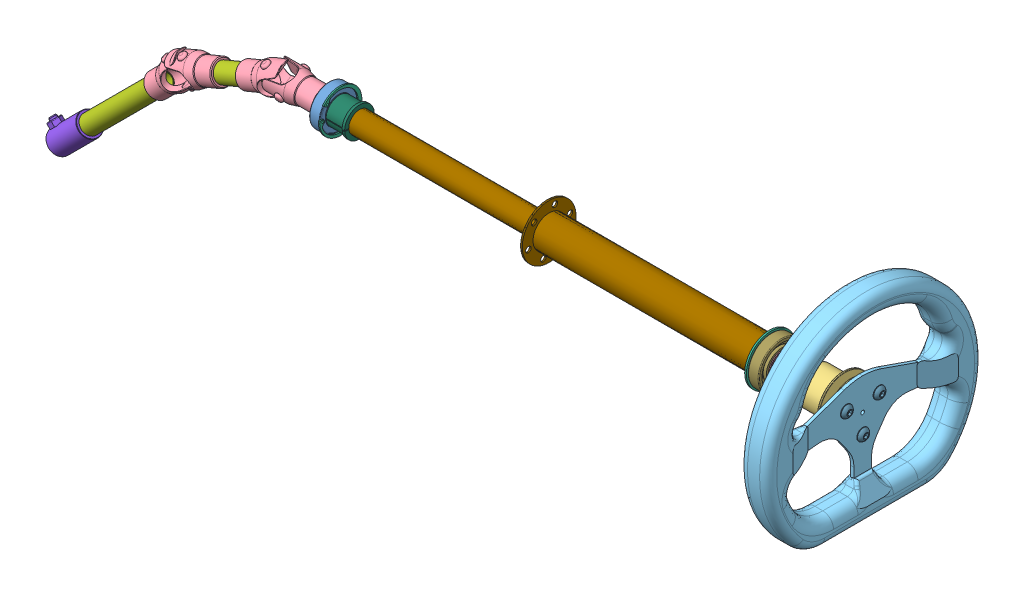
SolidWorks assembly SteeringColumn2SplineShaftFront, configuration Default. Lengths in mm.
Overall size (982.04 333.97 254.34).
24 component instances, 15 part files, 39 mates.
Components (placement in the parent):
- BearingBall6005-1: BearingBall6005 [Default] at (30.3546 0 0) x (0 1 0) z (0 0 1) size (47 12 47)
- WheelHubDisconnect-1: WheelHubDisconnect [Default] at (619.5484 0 0) x (1 0 0) z (0 -0.866763 0.498721) size (86.3 64.09 61.9)
  - SteeringWheelDisconnectSpline-1: SteeringWheelDisconnectSpline [Default] at origin size (55 25.4 25.4)
  - SteeringWheelDisconnect-1: SteeringWheelDisconnect [Default] at (31.3 0 0) x (0 0 -1) z (1 0 0) size (61.9 64.09 54.6)
- U-JointWoodward-1: U-JointWoodward [Default] at (-28.974 0 0) x (-1 0 0) z (0 -0.90881 -0.41721) size (73.55 38.86 33.16)
- SteeringWheel-1: SteeringWheel [Default] at (652.8042 0 0) x (0 -0.001477 0.999999) z (-1 0 0) size (254 227.58 56.05)
- Basic Internal Retaining Ring_am-1: Basic Internal Retaining Ring_am [B27.7M - 3BM1-47] at (36.3546 0 0) x (0 0.93649 -0.350695) z (-1 0 0) size (49.8 48.83 1.6)
- Basic Internal Retaining Ring_am-2: Basic Internal Retaining Ring_am [B27.7M - 3BM1-55] at (546.526 0 0) x (0 0.021414 -0.999771) z (1 0 0) size (58.4 57.21 2)
- U-JointDoubleMid-1: U-JointDoubleMid [Default] at (-87.086 -24.0708 0) x (-0.0561 0.135437 -0.989196) z (0.378549 -0.913898 -0.146596) size (42.36 158.5 46.32)
  - TubeSteering.75-1: TubeSteering.75 [DoubleUJoint] x (1 0 0) z (0 1 0) size (21.34 21.34 56.2)
  - U-JointWoodward-1: U-JointWoodward [Default] at (0 62.9 0) x (0 1 0) z (0.963512 0 -0.267666) size (73.55 38.86 33.16)
  - U-JointWoodward-2: U-JointWoodward [Default] at (0 -62.9 0) x (0 -1 0) z (0.963512 0 -0.267666) size (73.55 38.86 33.16)
- U-JointWoodward-2: U-JointWoodward [Default] at (-145.198 -48.1416 0) x (0.707107 0.707107 0) z (0.204327 -0.204327 0.95734) size (73.55 38.86 33.16)
- Coupler.75SmoothTo.625-36Spline-1: Coupler.75SmoothTo.625-36Spline [Default] at (-276.3664 -179.3099 0) x (0 0 -1) z (0.707107 0.707107 0) size (26.9 35.2 50.8)
- TubeSteering.75-1: TubeSteering.75 [RackToUJoint] at (-218.5957 -121.5393 0) x (-0.399395 0.399395 0.825208) z (0.707107 0.707107 0) size (21.34 21.34 138)
- SteeringColumn-1: SteeringColumn [Default] at (21.526 0 0) x (0 -0.699357 0.714773) z (-1 0 0) size (63.5 63.5 523.4)
- AdapterUJointToColumn-1: AdapterUJointToColumn [Default] at (18.526 0 0) x (0 0 1) z (-1 0 0) size (21.34 21.34 15)
- AdapterHubToColumn-1: AdapterHubToColumn [Default] at (553.026 0 0) x (0 -0.393267 0.919424) z (-1 0 0) size (41.1 41.1 29.62)
- Radial Ball Bearing_68_SKF-1: Radial Ball Bearing_68_SKF [SKF - 6006 - 14,SI,NC,14_68] at (553.026 0 0) x (-1 0 0) z (0 0.980666 0.195687) size (13 55 55)
- Basic External Retaining Ring_wti-1: Basic External Retaining Ring_wti [Truarc 5100-112 - S1.125] at (559.526 0 0) x (0 0 1) z (-1 0 0) size (31.9 34.77 1.27)
- Socket Button Head Cap Screw_AI-1: Socket Button Head Cap Screw_AI [SBHCSCREW 0.3125-18x0.5-HX-N] at (658.9764 11.0841 19.2638) x (-1 0 0) z (0 0.924225 0.381849) size (16.92 13.89 13.89)
- Socket Button Head Cap Screw_AI-2: Socket Button Head Cap Screw_AI [SBHCSCREW 0.3125-18x0.5-HX-N] at (658.9764 -22.225 -0.0328) x (-1 0 0) z (0 0.924225 0.381849) size (16.92 13.89 13.89)
- Socket Button Head Cap Screw_AI-3: Socket Button Head Cap Screw_AI [SBHCSCREW 0.3125-18x0.5-HX-N] at (658.9764 11.1409 -19.231) x (-1 0 0) z (0 0.924225 0.381849) size (16.92 13.89 13.89)
- SteeringColumnBush-1: SteeringColumnBush [Default] at (44.3672 0 0) x (0 0.051402 -0.998678) z (1 0 0) size (34.99 35 31.4)
Mates (geometry in assembly coordinates):
- Coincident7502: coincident: plane of assembly; plane of assembly; plane of WheelHubDisconnect-1/SteeringWheelDisconnect-1 through (650.8484 7.9047 13.7382) normal (1 0 0); plane of SteeringWheel-1 through (650.8484 0 0) normal (-1 0 0)
- Coincident75142: coincident: plane of BearingBall6005-1 through (30.3546 0 0) normal (0 1 0); plane of assembly through (0 0 0) normal (0 1 0)
- Concentric836224: concentric: cylinder of Basic Internal Retaining Ring_am-1 through (37.9546 0 0) axis (-1 0 0) radius 24.9; cylinder of BearingBall6005-1 through (3.674 0 0) axis (-1 0 0) radius 23.5
- Coincident75143: coincident: plane of BearingBall6005-1 through (36.3546 0 22.9) normal (1 0 0); plane of Basic Internal Retaining Ring_am-1 through (36.3546 0 0) normal (-1 0 0)
- Coincident75145: coincident: point of U-JointWoodward-1; point of U-JointDoubleMid-1/U-JointWoodward-1
- Coincident75146: coincident: line of U-JointDoubleMid-1/U-JointWoodward-1 through (-81.8253 -21.8917 0) axis (0.92388 0.382683 0)
- Coincident75149: coincident: line of U-JointWoodward-2 through (-185.6487 -88.5922 0) axis (0.707107 0.707107 0); plane of assembly
- Coincident75150: coincident: point of U-JointDoubleMid-1/U-JointWoodward-2; point of U-JointWoodward-2
- Concentric836225: concentric: cylinder of assembly; cylinder of assembly; cylinder of U-JointWoodward-2 through (-137.8738 -40.8173 0) axis (-0.707107 -0.707107 0) radius 9.525; cylinder of Coupler.75SmoothTo.625-36Spline-1 through (-276.3664 -179.3099 0) axis (0.707107 0.707107 0) radius 9.525
- Coincident75152: coincident: plane of assembly through (0 0 0) normal (0 0 1); plane of Coupler.75SmoothTo.625-36Spline-1 through (-276.3664 -179.3099 0) normal (0 0 -1); plane of assembly
- Angle2: planar angle = 2.748894 rad: line of U-JointWoodward-2 through (-172.318 -83.0705 0) axis (0.707107 0.707107 0); line of ? through (-79.0161 -20.7281 0) axis (-0.92388 -0.382683 0)
- Angle3: planar angle = 2.748894 rad: line of ? through (73.5543 -81.8253 -21.8917) axis (0 0.92388 0.382683); line of U-JointWoodward-1 through (28.2319 0 0) axis (-1 0 0)
- Concentric836226: concentric: cylinder of assembly; cylinder of assembly; cylinder of U-JointWoodward-2 through (-137.8738 -40.8173 0) axis (-0.707107 -0.707107 0) radius 9.525; cylinder of TubeSteering.75-1 through (-267.3861 -170.3296 0) axis (0.707107 0.707107 0) radius 10.668
- Coincident75154: coincident: plane of assembly; plane of assembly; plane of TubeSteering.75-1 through (-258.4058 -161.3494 0) normal (-0.707107 -0.707107 0); plane of Coupler.75SmoothTo.625-36Spline-1 through (-258.4058 -161.3494 0) normal (0.707107 0.707107 0)
- Concentric836231: concentric: cylinder of assembly; cylinder of assembly; cylinder of U-JointWoodward-1 through (-39.3321 0 0) axis (1 0 0) radius 9.525; cylinder of AdapterUJointToColumn-1 through (-33.4878 0 0) axis (-1 0 0) radius 9.525
- Coincident75158: coincident: plane of assembly; plane of assembly; plane of U-JointWoodward-1 through (18.526 0 0) normal (1 0 0); plane of AdapterUJointToColumn-1 through (18.526 9.525 0) normal (-1 0 0)
- Coincident75160: coincident: plane of assembly; plane of assembly; plane of SteeringColumn-1 through (21.526 0 0) normal (-1 0 0); plane of AdapterUJointToColumn-1 through (21.526 10.668 0) normal (1 0 0)
- Concentric836232: concentric: cylinder of assembly; cylinder of BearingBall6005-1 through (3.674 0 0) axis (-1 0 0) radius 12.5; cylinder of SteeringColumn-1 through (283.226 0 0) axis (-1 0 0) radius 12.7
- Concentric836233: concentric: cylinder of assembly; cylinder of assembly; cylinder of SteeringColumn-1 through (283.226 0 0) axis (-1 0 0) radius 10.7; cylinder of AdapterUJointToColumn-1 through (-33.4878 0 0) axis (-1 0 0) radius 10.5
- Concentric836238: concentric: cylinder of assembly; cylinder of assembly; cylinder of SteeringColumn-1 through (544.926 0 0) axis (-1 0 0) radius 17.85; cylinder of AdapterHubToColumn-1 through (478.2216 0 0) axis (-1 0 0) radius 17.85
- Coincident75165: coincident: plane of assembly; plane of assembly; plane of SteeringColumn-1 through (544.926 0 0) normal (1 0 0); plane of AdapterHubToColumn-1 through (544.926 18.8942 8.0816) normal (-1 0 0)
- Concentric836239: concentric: cylinder of assembly; cylinder of assembly; cylinder of AdapterHubToColumn-1 through (478.2216 0 0) axis (-1 0 0) radius 15; cylinder of Radial Ball Bearing_68_SKF-1 through (573.6635 0 0) axis (-1 0 0) radius 15
- Coincident75166: coincident: plane of assembly; plane of assembly; plane of AdapterHubToColumn-1 through (546.526 13.7914 5.899) normal (1 0 0); plane of Radial Ball Bearing_68_SKF-1 through (546.526 -3.131 15.6907) normal (-1 0 0)
- Concentric8362411: concentric: cylinder of assembly; cylinder of assembly; cylinder of AdapterHubToColumn-1 through (478.2216 0 0) axis (-1 0 0) radius 13.45; cylinder of Basic External Retaining Ring_wti-1 through (560.796 0 0) axis (-1 0 0) radius 13.4493
- Coincident751681: coincident: plane of assembly; plane of assembly; plane of AdapterHubToColumn-1 through (559.526 12.3663 5.2894) normal (1 0 0); plane of Basic External Retaining Ring_wti-1 through (559.526 0 0) normal (-1 0 0)
- Concentric8362421: concentric: cylinder of assembly; cylinder of assembly; cylinder of Basic Internal Retaining Ring_am-2 through (544.526 0 0) axis (1 0 0) radius 29.2; cylinder of Radial Ball Bearing_68_SKF-1 through (573.6635 0 0) axis (-1 0 0) radius 27.5
- Coincident7516831: coincident: plane of assembly; plane of assembly; plane of Basic Internal Retaining Ring_am-2 through (546.526 0 0) normal (1 0 0); plane of Radial Ball Bearing_68_SKF-1 through (546.526 -5.1857 25.9877) normal (-1 0 0)
- Concentric8362422: concentric: cylinder of assembly; cylinder of assembly; cylinder of SteeringWheel-1 through (777.8484 11.0841 19.2638) axis (-1 0 0) radius 3.9688; cylinder of Socket Button Head Cap Screw_AI-1 through (658.9764 11.0841 19.2638) axis (1 0 0) radius 6.9469
- Coincident7516832: coincident: plane of assembly; plane of assembly; plane of SteeringWheel-1 through (654.76 0 0) normal (1 0 0); plane of Socket Button Head Cap Screw_AI-1 through (654.76 9.5686 22.9318) normal (-1 0 0)
- Concentric8362423: concentric: cylinder of assembly; cylinder of assembly; cylinder of SteeringWheel-1 through (777.8484 -22.225 -0.0328) axis (-1 0 0) radius 3.9688; cylinder of Socket Button Head Cap Screw_AI-2 through (658.9764 -22.225 -0.0328) axis (1 0 0) radius 6.9469
- Coincident7516833: coincident: plane of assembly; plane of assembly; plane of SteeringWheel-1 through (654.76 0 0) normal (1 0 0); plane of Socket Button Head Cap Screw_AI-2 through (654.76 -23.7404 3.6352) normal (-1 0 0)
- Concentric8362424: concentric: cylinder of assembly; cylinder of assembly; cylinder of SteeringWheel-1 through (777.8484 11.1409 -19.231) axis (-1 0 0) radius 3.9688; cylinder of Socket Button Head Cap Screw_AI-3 through (658.9764 11.1409 -19.231) axis (1 0 0) radius 6.9469
- Coincident7516834: coincident: plane of assembly; plane of assembly; plane of SteeringWheel-1 through (654.76 0 0) normal (1 0 0); plane of Socket Button Head Cap Screw_AI-3 through (654.76 9.6254 -15.563) normal (-1 0 0)
- Concentric8362425: concentric: cylinder of WheelHubDisconnect-1/SteeringWheelDisconnectSpline-1 through (638.7167 0 0) axis (1 0 0) radius 9.525; cylinder of AdapterHubToColumn-1 through (478.2216 0 0) axis (-1 0 0) radius 9.525
- Coincident7516835: coincident: circle of WheelHubDisconnect-1/SteeringWheelDisconnectSpline-1; circle of AdapterHubToColumn-1
- Concentric8362426: concentric: cylinder of assembly; cylinder of WheelHubDisconnect-1/SteeringWheelDisconnect-1 through (660.7108 0 0) axis (1 0 0) radius 15.85; line of SteeringWheel-1 through (36.5216 652.8042 0) axis (0 -1 0)
- Concentric8362427: concentric: cylinder of assembly; cylinder of assembly; cylinder of WheelHubDisconnect-1/SteeringWheelDisconnect-1 through (596.2474 11.0841 19.2638) axis (1 0 0) radius 3.175; cylinder of Socket Button Head Cap Screw_AI-1 through (658.9764 11.0841 19.2638) axis (1 0 0) radius 3.9688
- Coincident7516836: coincident: plane of assembly; plane of assembly; plane of U-JointWoodward-2 through (-178.7856 -81.7291 0) normal (-0.707107 -0.707107 0); plane of TubeSteering.75-1 through (-178.7856 -81.7291 0) normal (0.707107 0.707107 0)
- Concentric8362428: concentric: cylinder of assembly; cylinder of assembly; cylinder of SteeringColumn-1 through (283.226 0 0) axis (-1 0 0) radius 12.7; cylinder of SteeringColumnBush-1 through (112.2235 0 0) axis (1 0 0) radius 12.7
